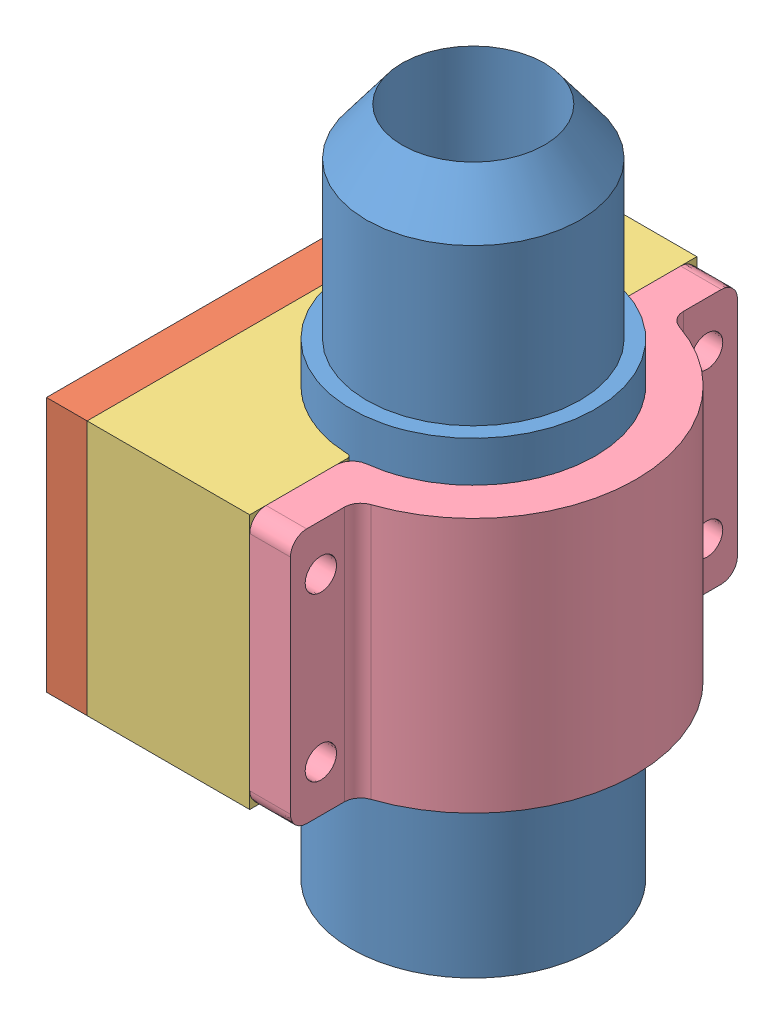
SolidWorks assembly NozzleClampAssembly, configuration Default. Lengths in mm.
Overall size (57.15 107.2 69.85).
14 component instances, 7 part files, 18 mates.
Components (placement in the parent):
- Nozzle_C-1: Nozzle_C [Default] at (31.75 -49.911 0) x (0.951012 0 -0.309152) z (0.309152 0 0.951012) size (38.1 107.2 38.1)
- attachment disk_C-1: attachment disk_C [Default] at (6.35 0 0) x (0 0 -1) z (0 1 0) size (69.85 6.63 39.88)
- Clamp_B-1: Clamp_B [Default] at (31.75 19.939 0) x (0 0 1) z (-1 0 0) size (69.85 39.88 25.4)
- Clamp_A-1: Clamp_A [Default] at (31.75 19.939 0) x (0 0 1) z (-1 0 0) size (69.85 39.88 25.4)
- 91266A258_Thread-Locking Hex Drive Flat Head Screws-1: 91266A258_Thread-Locking Hex Drive Flat Head Screws [91266A258] at (31.75 0 25.4) x (0 -0.258689 -0.965961) z (1 0 0) (suppressed, hidden)
- 91266A254_Thread-Locking Hex Drive Flat Head Screws-1: 91266A254_Thread-Locking Hex Drive Flat Head Screws [91266A254] at (6.35 11.1369 11.1369) x (0 0 -1) z (1 0 0) (suppressed, hidden)
- 91266A258_Thread-Locking Hex Drive Flat Head Screws-2: 91266A258_Thread-Locking Hex Drive Flat Head Screws [91266A258] at (31.75 0 -25.4) x (0 -0.258689 0.965961) z (1 0 0) (suppressed, hidden)
- 91251A345_Black-Oxide Alloy Steel Socket Head Screw-1: 91251A345_Black-Oxide Alloy Steel Socket Head Screw [91251A345] at (30.988 -12.7 30.1625) x (0 0 -1) z (1 0 0) (suppressed, hidden)
- 91251A345_Black-Oxide Alloy Steel Socket Head Screw-2: 91251A345_Black-Oxide Alloy Steel Socket Head Screw [91251A345] at (30.988 12.7 30.1625) x (0 0 1) z (1 0 0) (suppressed, hidden)
- 91251A345_Black-Oxide Alloy Steel Socket Head Screw-3: 91251A345_Black-Oxide Alloy Steel Socket Head Screw [91251A345] at (30.988 -12.7 -30.1625) x (0 0 -1) z (1 0 0) (suppressed, hidden)
- 91251A345_Black-Oxide Alloy Steel Socket Head Screw-4: 91251A345_Black-Oxide Alloy Steel Socket Head Screw [91251A345] at (30.988 12.7 -30.1625) x (0 0 1) z (1 0 0) (suppressed, hidden)
- 91266A254_Thread-Locking Hex Drive Flat Head Screws-9: 91266A254_Thread-Locking Hex Drive Flat Head Screws [91266A254] at (6.35 -11.1369 11.1369) x (0 0 -1) z (1 0 0) (suppressed, hidden)
- 91266A254_Thread-Locking Hex Drive Flat Head Screws-10: 91266A254_Thread-Locking Hex Drive Flat Head Screws [91266A254] at (6.35 11.1369 -11.1369) x (0 0 1) z (1 0 0) (suppressed, hidden)
- 91266A254_Thread-Locking Hex Drive Flat Head Screws-11: 91266A254_Thread-Locking Hex Drive Flat Head Screws [91266A254] at (6.35 -11.1369 -11.1369) x (0 0 1) z (1 0 0) (suppressed, hidden)
Mates (geometry in assembly coordinates):
- Concentric4: concentric anti-aligned: cylinder of Clamp_B-1 through (31.75 -19.939 0) axis (0 1 0) radius 19.05; cylinder of Nozzle_C-1 through (31.75 26.289 0) axis (0 -1 0) radius 19.05
- Distance4: distance = 6.35 mm aligned: plane of Clamp_B-1 through (31.75 19.939 0) normal (0 1 0); plane of Nozzle_C-1 through (31.75 26.289 0) normal (0 1 0)
- Coincident22: coincident aligned: plane of Clamp_B-1 through (31.75 19.939 0) normal (0 1 0); plane of attachment disk_C-1 through (0 19.939 -34.925) normal (0 1 0)
- Coincident23: coincident aligned: plane of Clamp_B-1 through (6.35 -19.939 34.925) normal (0 0 1); plane of attachment disk_C-1 through (0 19.939 34.925) normal (0 0 1)
- Coincident24: coincident anti-aligned: plane of Clamp_B-1 through (6.35 -19.939 -34.925) normal (-1 0 0); plane of attachment disk_C-1 through (6.35 0 0) normal (1 0 0)
- Coincident5: coincident anti-aligned: plane of Clamp_B-1 through (31.75 -19.939 19.05) normal (1 0 0); plane of Clamp_A-1 through (31.75 -19.939 19.05) normal (-1 0 0)
- Coincident6: coincident aligned: plane of Clamp_B-1 through (31.75 19.939 0) normal (0 1 0); plane of Clamp_A-1 through (31.75 19.939 0) normal (0 1 0)
- Coincident7: coincident aligned: plane of Clamp_B-1 through (31.75 -19.939 -34.925) normal (0 0 -1); plane of Clamp_A-1 through (31.75 -19.939 -34.925) normal (0 0 -1)
- Symmetric1: symmetric aligned: plane of Clamp_B-1 through (6.35 -19.939 34.925) normal (0 0 1); plane of Clamp_B-1 through (31.75 -19.939 -34.925) normal (0 0 -1)
- Symmetric2: symmetric aligned: plane of Clamp_B-1 through (31.75 -19.939 0) normal (0 -1 0); plane of Clamp_B-1 through (31.75 19.939 0) normal (0 1 0)
- Parallel2: parallel aligned: plane of Clamp_B-1 through (31.75 19.939 0) normal (0 1 0)
- Coincident29: coincident anti-aligned: plane of attachment disk_C-1 through (0 0 0) normal (-1 0 0)
- Concentric6: concentric aligned: circle of Clamp_B-1; cylinder of 91266A258_Thread-Locking Hex Drive Flat Head Screws-1 through (31.75 0 25.4) axis (1 0 0) radius 5.2197
- Concentric7: concentric aligned: cone of attachment disk_C-1 through (6.35 11.1369 11.1369) axis (-1 0 0); cone of 91266A254_Thread-Locking Hex Drive Flat Head Screws-1 through (3.1242 11.1369 11.1369) axis (-1 0 0)
- Coincident33: coincident aligned: plane of attachment disk_C-1 through (6.35 0 0) normal (1 0 0); plane of 91266A254_Thread-Locking Hex Drive Flat Head Screws-1 through (6.35 8.7239 11.1369) normal (1 0 0)
- Coincident37: coincident aligned: plane of Clamp_B-1 through (31.75 -19.939 19.05) normal (1 0 0); plane of 91266A258_Thread-Locking Hex Drive Flat Head Screws-1 through (31.75 -2.3309 26.0242) normal (1 0 0)
- Concentric12: concentric anti-aligned: cylinder of Clamp_A-1 through (38.1 -12.7 30.1625) axis (1 0 0) radius 2.4574; cylinder of 91251A345_Black-Oxide Alloy Steel Socket Head Screw-1 through (19.05 -12.7 30.1625) axis (-1 0 0) radius 3.9688
- Coincident38: coincident anti-aligned: plane of Clamp_A-1 through (38.1 -19.939 34.925) normal (1 0 0); plane of 91251A345_Black-Oxide Alloy Steel Socket Head Screw-1 through (38.1 -12.7 33.8899) normal (-1 0 0)
